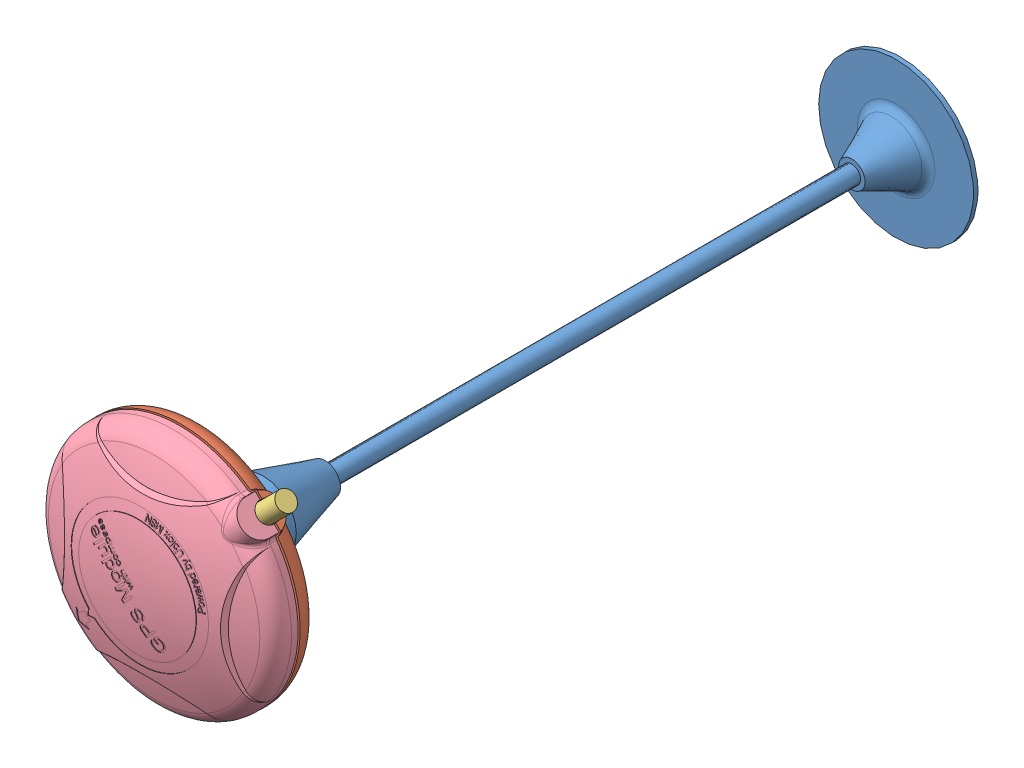
SolidWorks assembly GPS, configuration Default. Lengths in mm.
Overall size (76.65 76.65 173.9).
9 component instances, 5 part files, 2 mates.
Components (placement in the parent):
- mount-1: mount [Default] at (-12.6681 -14.5451 78.6227) size (40 40 158)
- GPS модуль Ublox NEO-M8N-0-01-1: GPS модуль Ublox NEO-M8N-0-01 [По умолчанию] at (-13.9191 -14.763 240.4558) x (1 0 0) z (0 -1 0) size (76.65 16.3 76.65)
  - Основание-1: Основание [По умолчанию] at (1.251 2.1668 -0.218) size (53.7 6.4 53.7)
  - Модуль GPS Ublox NEO-M8N-0-01-1: Модуль GPS Ublox NEO-M8N-0-01 [По умолчанию] at (1.251 1.9668 -0.218) x (0 0 -1) z (1 0 0) size (40.83 9.84 40.83)
  - Крышка-1: Крышка [По умолчанию] at (1.251 1.0668 -0.218) x (-0.707107 0 -0.707107) z (0.707107 0 -0.707107) size (53.6 11.16 54.8)
  - pan head cross recess screw_din-12: pan head cross recess screw_din [DIN EN ISO 7045 - M1.6 x 5 - Z - 5N] at (18.751 -2.4332 -0.218) x (0 1 0) z (0 0 1) size (6.27 3.2 3.2)
  - pan head cross recess screw_din-16: pan head cross recess screw_din [DIN EN ISO 7045 - M1.6 x 5 - Z - 5N] at (1.251 -2.4332 -17.718) x (0 1 0) z (1 0 0) size (6.27 3.2 3.2)
  - pan head cross recess screw_din-17: pan head cross recess screw_din [DIN EN ISO 7045 - M1.6 x 5 - Z - 5N] at (-16.249 -2.4332 -0.218) x (0 1 0) z (0 0 -1) size (6.27 3.2 3.2)
  - pan head cross recess screw_din-18: pan head cross recess screw_din [DIN EN ISO 7045 - M1.6 x 5 - Z - 5N] at (1.251 -2.4332 17.282) x (0 1 0) z (-1 0 0) size (6.27 3.2 3.2)
Mates (geometry in assembly coordinates):
- Coincident1: coincident anti-aligned: plane of mount-1 through (-17.6681 -3.6364 236.6227) normal (0 0 1); plane of GPS модуль Ublox NEO-M8N-0-01-1/Основание-1 through (-33.3681 -14.5451 236.6227) normal (0 0 -1)
- Coincident6: coincident anti-aligned: line of mount-1 through (-12.6681 -14.5451 234.6227) axis (0 0 -1); line of GPS модуль Ublox NEO-M8N-0-01-1/Крышка-1 through (-12.6681 -14.5451 241.3922) axis (0 0 1)
